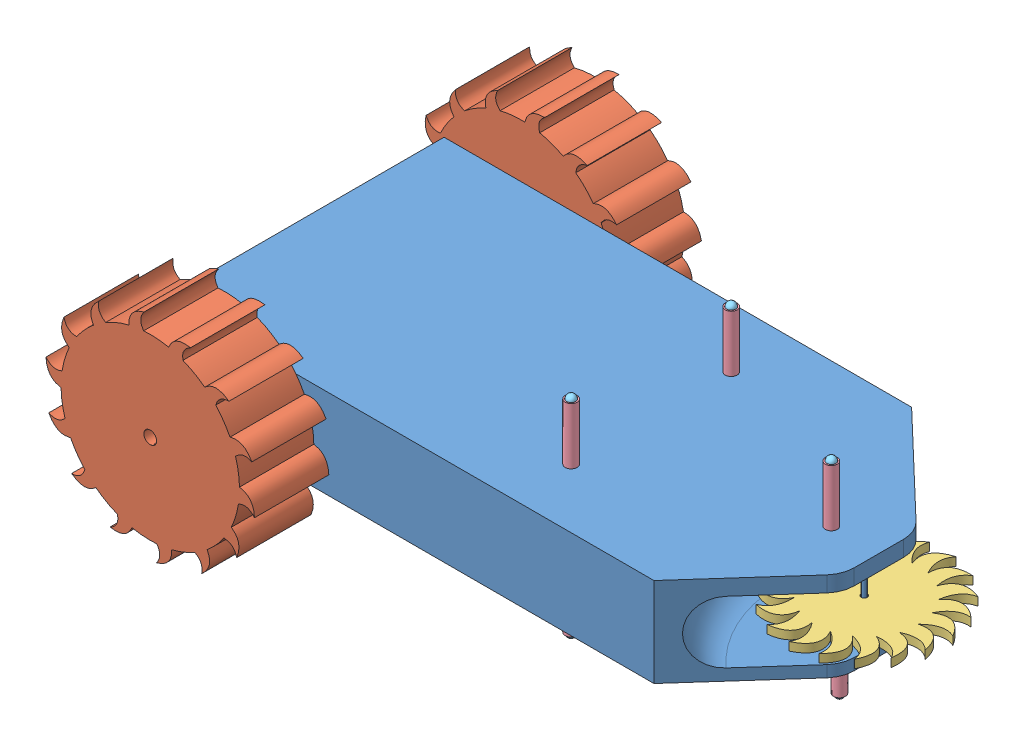
SolidWorks assembly RoboWar, configuration Default. Lengths in mm.
Overall size (260.32 98.74 149.81).
17 component instances, 6 part files, 26 mates.
Components (placement in the parent):
- Chasset-1: Chasset [Default] at (81.1347 93.9911 149.6936) size (194.35 30 114)
- Tire-1: Tire [Default] at (23.8134 108.9911 207.0603) x (0.792096 -0.610396 0) z (-0.610396 -0.792096 0) size (71.04 25 69.92)
- Tire-2: Tire [Default] at (23.8134 108.9911 82.2454) x (0.999213 -0.039674 0) z (-0.039674 -0.999213 0) size (71.04 25 69.92)
- Cutter-1: Cutter [Default] at (190.2993 106.8923 158.2243) x (-0.932646 0 -0.360794) z (0.360794 0 -0.932646) size (52.82 2.79 52.88)
- Castor-1: Castor [Default] at (117.3516 123.9911 184.0603) size (4 19 4)
- Castor-2: Castor [Default] at (117.3516 123.9911 130.2454) size (4 19 4)
- Castor-3: Castor [Default] at (179.1515 123.9911 158.359) size (4 19 4)
- Wheel for Castor-1: Wheel for Castor [Default] at (117.3516 142.9911 184.0603) size (3 3 3)
- Wheel for Castor-2: Wheel for Castor [Default] at (179.1515 142.9911 158.359) x (-0.813719 -0.370654 -0.447747) z (-0.081575 -0.689861 0.719331) size (3 3 3)
- Wheel for Castor-3: Wheel for Castor [Default] at (117.3516 142.9911 130.2454) size (3 3 3)
- Castor-5: Castor [Default] at (118.9657 93.9911 131.4264) x (0.61597 0 -0.78777) z (-0.78777 0 -0.61597) size (4 19 4)
- Wheel for Castor-5: Wheel for Castor [Default] at (117.3516 74.9911 184.0603) size (3 3 3)
- Castor-6: Castor [Default] at (117.3516 93.9911 184.0603) x (0.311412 0 0.950275) z (0.950275 0 -0.311412) size (4 19 4)
- Wheel for Castor-6: Wheel for Castor [Default] at (118.9657 74.9911 131.4264) size (3 3 3)
- Castor-7: Castor [Default] at (180.1329 93.9911 156.6163) x (-0.96807 0 -0.250679) z (-0.250679 0 0.96807) size (4 19 4)
- Wheel for Castor-7: Wheel for Castor [Default] at (180.1329 74.9911 156.6163) x (0.871306 0.31105 -0.37957) z (0.353376 0.139013 0.925095) size (3 3 3)
- Flipper-1: Flipper [Default] at (-8.759 108.444 114.6513) x (0.809685 -0.586865 0) z (-0.586865 -0.809685 0) size (7.22 85 54.6)
Mates (geometry in assembly coordinates):
- Concentric2: concentric aligned: cylinder of Chasset-1 through (23.8134 108.9911 100.0603) axis (0 0 1) radius 2.1462; cylinder of Tire-1 through (23.8134 108.9911 207.0603) axis (0 0 1) radius 2.15
- Concentric4: concentric aligned: cylinder of Chasset-1 through (23.8134 108.9911 100.0603) axis (0 0 1) radius 2.1462; cylinder of Tire-2 through (23.8134 108.9911 82.2454) axis (0 0 1) radius 2.15
- Distance1: distance = 3 mm anti-aligned: plane of Tire-2 through (23.8134 108.9911 107.2454) normal (0 0 1); plane of Chasset-1 through (158.0227 123.9911 110.2454) normal (0 0 -1)
- Distance2: distance = 3 mm anti-aligned: plane of Tire-1 through (23.8134 108.9911 207.0603) normal (0 0 -1); plane of Chasset-1 through (0.8039 123.9911 204.0603) normal (0 0 1)
- Concentric5: concentric aligned: cylinder of Chasset-1 through (190.2339 93.9911 158.359) axis (0 1 0) radius 0.7629; cylinder of Cutter-1 through (190.2339 106.4973 158.359) axis (0 1 0) radius 1.0602
- Distance6: distance = 11.43 mm aligned: plane of Cutter-1 through (190.2339 109.2873 158.359) normal (0 1 0); plane of Chasset-1 through (176.6579 97.8573 191.2235) normal (0 1 0)
- Distance7: distance = 0 mm anti-aligned: plane of Castor-3 through (179.1515 123.9911 158.359) normal (0 -1 0); plane of Chasset-1 through (81.1347 123.9911 149.6936) normal (0 1 0)
- Concentric6: concentric: cylinder of assembly; point of Chasset-1; cylinder of Castor-3 through (179.1515 142.9911 158.359) axis (0 -1 0) radius 2
- Concentric7: concentric: cylinder of assembly; point of Chasset-1; cylinder of Castor-2 through (117.3516 142.9911 130.2454) axis (0 -1 0) radius 2
- Distance9: distance = 0 mm anti-aligned: plane of Castor-2 through (117.3516 123.9911 130.2454) normal (0 -1 0); plane of Chasset-1 through (81.1347 123.9911 149.6936) normal (0 1 0)
- Concentric8: concentric: cylinder of assembly; point of Chasset-1; cylinder of Castor-1 through (117.3516 142.9911 184.0603) axis (0 -1 0) radius 2
- Distance10: distance = 0 mm anti-aligned: plane of Castor-1 through (117.3516 123.9911 184.0603) normal (0 -1 0); plane of Chasset-1 through (81.1347 123.9911 149.6936) normal (0 1 0)
- Concentric9: concentric: sphere of Castor-3; sphere of Wheel for Castor-2
- Concentric10: concentric: sphere of Castor-2; sphere of Wheel for Castor-3
- Concentric11: concentric: sphere of Castor-1; sphere of Wheel for Castor-1
- Coincident13: coincident: cylinder of assembly; point of Chasset-1; cylinder of Castor-7 through (180.1329 74.9911 156.6163) axis (0 1 0) radius 2
- Distance11: distance = 0 mm anti-aligned: plane of Castor-7 through (180.1329 93.9911 156.6163) normal (0 1 0); plane of Chasset-1 through (81.1347 93.9911 149.6936) normal (0 -1 0)
- Concentric15: concentric: cylinder of assembly; point of Chasset-1; cylinder of Castor-6 through (117.3516 74.9911 184.0603) axis (0 1 0) radius 2
- Distance12: distance = 0 mm anti-aligned: plane of Castor-6 through (117.3516 93.9911 184.0603) normal (0 1 0); plane of Chasset-1 through (81.1347 93.9911 149.6936) normal (0 -1 0)
- Coincident21: coincident: cylinder of assembly; point of Chasset-1; cylinder of Castor-5 through (118.9657 74.9911 131.4264) axis (0 1 0) radius 2
- Distance13: distance = 0 mm anti-aligned: plane of Castor-5 through (118.9657 93.9911 131.4264) normal (0 1 0); plane of Chasset-1 through (81.1347 93.9911 149.6936) normal (0 -1 0)
- Concentric16: concentric: sphere of Castor-7; sphere of Wheel for Castor-7
- Concentric17: concentric: sphere of Castor-5; sphere of Wheel for Castor-6
- Concentric18: concentric: sphere of Wheel for Castor-5; sphere of Castor-6
- Concentric19: concentric aligned: cylinder of Chasset-1 through (1.2252 121.1676 111.3194) axis (0 0 1) radius 0.25; cylinder of Flipper-1 through (1.2252 121.1676 114.6513) axis (0 0 1) radius 0.5015
- Distance14: distance = 1.665 mm anti-aligned: plane of Flipper-1 through (-8.759 108.444 114.6513) normal (0 0 -1); plane of Chasset-1 through (5.8039 121.9422 112.9863) normal (0 0 1)
